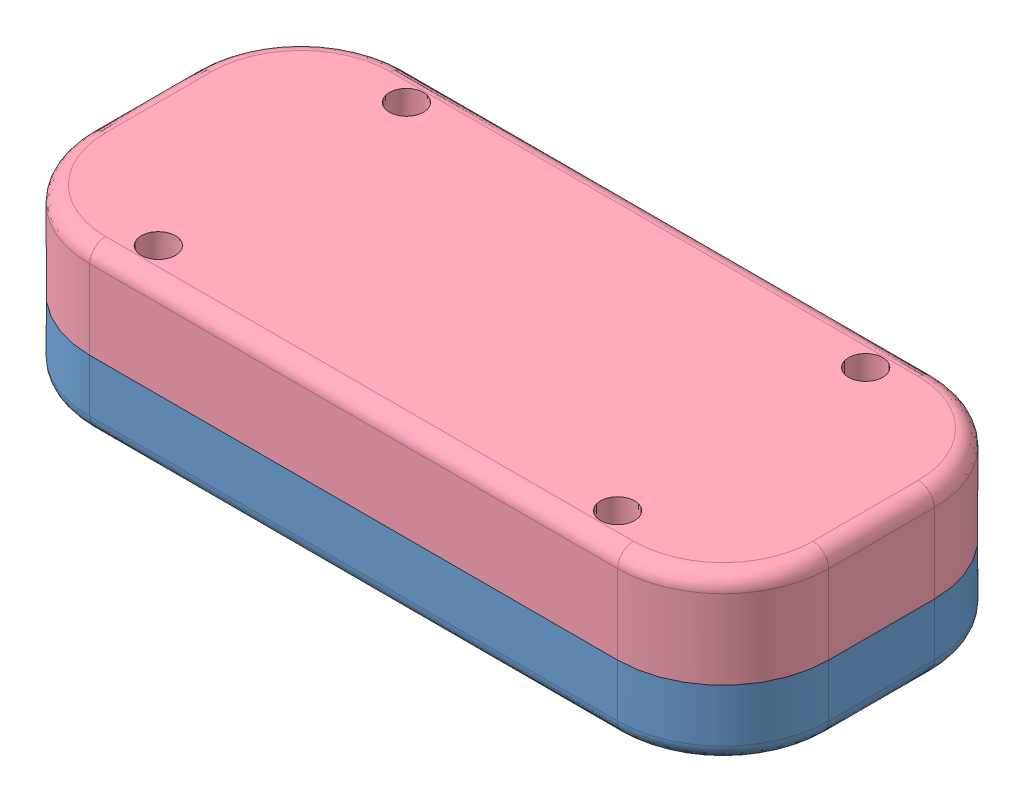
SolidWorks assembly TES, configuration Default. Lengths in mm.
Overall size (140 31 62.5).
89 component instances, 21 part files, 17 mates.
Components (placement in the parent):
- TES-top-1: TES-top [Default] at (48.5588 53.8768 118.0307) size (140 13 60)
- SPI-TFT-320X240-1: SPI-TFT-320X240 [Default] at (50.0588 62.3768 118.0307) x (1 0 0) z (0 0 -1) size (77 14 43)
- D-Pad-1: D-Pad [Default] at (-3.5412 66.8768 117.9307) x (1 0 0) z (0 -1 0) size (25 40 7)
- D-Pad-2: D-Pad [Default] at (99.6588 66.8768 117.9307) x (1 0 0) z (0 -1 0) size (25 40 7)
- TES-bottom-1: TES-bottom [Default] at (48.5588 84.8768 118.0307) x (1 0 0) z (0 0 -1) size (140 18 60)
- RapberryPiZero-1: RapberryPiZero [Default] at (-2.6976 88.9734 113.4764) x (-1 0 0) z (0 0 1) size (65 4.45 30.6)
  - Raspberry_pizero_PCB-1: Raspberry_pizero_PCB [Default] at (-51.2564 20.0966 13.0542) size (65 1 30)
  - Micro USB_input_female (short)-SMT-1: Micro USB_input_female (short)-SMT [Default] at (-42.3564 22.3216 25.8042) size (7.98 2.94 5.43)
  - Micro USB_input_female (short)-SMT-2: Micro USB_input_female (short)-SMT [Default] at (-29.7564 22.3216 25.8042) size (7.98 2.94 5.43)
  - 0204 - Capacitor-1: 0204 - Capacitor [Default] at (-62.4121 21.3466 11.2398) size (1 0.5 0.6)
  - 0204 - Capacitor-2: 0204 - Capacitor [Default] at (-62.4121 21.3466 12.2528) size (1 0.5 0.6)
  - 0204 - Capacitor-3: 0204 - Capacitor [Default] at (-61.8122 21.3466 13.3136) size (1 0.5 0.6)
  - 0204 - Capacitor-4: 0204 - Capacitor [Default] at (-61.8122 21.3466 14.2646) size (1 0.5 0.6)
  - 0204 - Capacitor-5: 0204 - Capacitor [Default] at (-61.8122 21.3466 15.241) size (1 0.5 0.6)
  - 0204 - Capacitor-6: 0204 - Capacitor [Default] at (-61.8122 21.3466 16.2144) size (1 0.5 0.6)
  - 0204 - Capacitor-7: 0204 - Capacitor [Default] at (-61.8122 21.3466 17.2416) size (1 0.5 0.6)
  - 0204 - Capacitor-8: 0204 - Capacitor [Default] at (-62.5919 21.3466 20.9695) size (1 0.5 0.6)
  - 0204 - Capacitor-9: 0204 - Capacitor [Default] at (-62.5919 21.3466 21.919) size (1 0.5 0.6)
  - 0204 - Capacitor-10: 0204 - Capacitor [Default] at (-60.4584 21.3466 22.3712) x (0 0 1) z (-1 0 0) size (1 0.5 0.6)
  - 0204 - Capacitor-11: 0204 - Capacitor [Default] at (-60.0807 21.3466 22.3712) x (0 0 -1) z (1 0 0) size (1 0.5 0.6)
  - 0204 - Capacitor-12: 0204 - Capacitor [Default] at (-59.0466 21.3466 22.3712) x (0 0 -1) z (1 0 0) size (1 0.5 0.6)
  - 0204 - Capacitor-13: 0204 - Capacitor [Default] at (-52.6496 21.3466 22.316) x (0 0 1) z (-1 0 0) size (1 0.5 0.6)
  - 0204 - Capacitor-14: 0204 - Capacitor [Default] at (-52.25 21.3466 22.316) x (0 0 -1) z (1 0 0) size (1 0.5 0.6)
  - 0204 - Capacitor-15: 0204 - Capacitor [Default] at (-51.2398 21.3466 22.316) x (0 0 -1) z (1 0 0) size (1 0.5 0.6)
  - 0204 - Capacitor-16: 0204 - Capacitor [Default] at (-49.1841 21.3466 22.316) x (0 0 -1) z (1 0 0) size (1 0.5 0.6)
  - 0204 - Capacitor-17: 0204 - Capacitor [Default] at (-48.1448 21.3466 22.316) x (0 0 -1) z (1 0 0) size (1 0.5 0.6)
  - 0204 - Capacitor-18: 0204 - Capacitor [Default] at (-46.475 21.3466 21.113) size (1 0.5 0.6)
  - 0204 - Capacitor-19: 0204 - Capacitor [Default] at (-45.7322 21.3466 20.0663) size (1 0.5 0.6)
  - 0204 - Capacitor-20: 0204 - Capacitor [Default] at (-45.7322 21.3466 19.0675) size (1 0.5 0.6)
  - 0204 - Capacitor-21: 0204 - Capacitor [Default] at (-45.7322 21.3466 18.1249) size (1 0.5 0.6)
  - 0204 - Capacitor-22: 0204 - Capacitor [Default] at (-45.7322 21.3466 17.1095) size (1 0.5 0.6)
  - 0204 - Capacitor-23: 0204 - Capacitor [Default] at (-46.3457 21.3466 16.1412) size (1 0.5 0.6)
  - 0204 - Capacitor-24: 0204 - Capacitor [Default] at (-46.3457 21.3466 15.1229) size (1 0.5 0.6)
  - 0204 - Capacitor-25: 0204 - Capacitor [Default] at (-46.3457 21.3466 14.0197) size (1 0.5 0.6)
  - 0204 - Capacitor-26: 0204 - Capacitor [Default] at (-46.3457 21.3466 12.9589) size (1 0.5 0.6)
  - 0204 - Capacitor-27: 0204 - Capacitor [Default] at (-43.6156 21.3466 13.1418) size (1 0.5 0.6)
  - 0204 - Capacitor-28: 0204 - Capacitor [Default] at (-43.6156 21.3466 10.1424) size (1 0.5 0.6)
  - 0204 - Capacitor-29: 0204 - Capacitor [Default] at (-48.9117 21.3466 7.6917) size (1 0.5 0.6)
  - 0204 - Capacitor-30: 0204 - Capacitor [Default] at (-55.4926 21.3466 7.2526) x (0 0 -1) z (1 0 0) size (1 0.5 0.6)
  - 0204 - Capacitor-31: 0204 - Capacitor [Default] at (-53.7932 21.3466 7.2526) x (0 0 1) z (-1 0 0) size (1 0.5 0.6)
  - 0204 - Capacitor-32: 0204 - Capacitor [Default] at (-59.8477 21.3466 7.2526) x (0 0 1) z (-1 0 0) size (1 0.5 0.6)
  - 0204- Resistor-15: 0204- Resistor [Default] at (-43.6109 21.4522 15.4193) x (-1 0 0) z (0 -1 0) size (0.99 0.51 0.36)
  - 0204- Resistor-14: 0204- Resistor [Default] at (-43.6109 21.4522 14.4127) x (-1 0 0) z (0 -1 0) size (0.99 0.51 0.36)
  - 0204- Resistor-13: 0204- Resistor [Default] at (-43.6109 21.4522 12.4047) x (-1 0 0) z (0 -1 0) size (0.99 0.51 0.36)
  - 0204- Resistor-4: 0204- Resistor [Default] at (-42.6936 21.4522 18.4076) x (-1 0 0) z (0 -1 0) size (0.99 0.51 0.36)
  - 0204- Resistor-5: 0204- Resistor [Default] at (-39.831 21.4522 18.1462) x (0 0 1) z (0 -1 0) size (0.99 0.51 0.36)
  - 0204- Resistor-7: 0204- Resistor [Default] at (-61.8169 21.4522 19.8533) x (-1 0 0) z (0 -1 0) size (0.99 0.51 0.36)
  - 0204- Resistor-8: 0204- Resistor [Default] at (-61.8169 21.4522 18.5178) x (-1 0 0) z (0 -1 0) size (0.99 0.51 0.36)
  - 0204- Resistor-9: 0204- Resistor [Default] at (-79.148 21.4522 17.7279) x (-1 0 0) z (0 -1 0) size (0.99 0.51 0.36)
  - 0204- Resistor-10: 0204- Resistor [Default] at (-56.0985 21.4522 7.2479) x (0 0 -1) z (0 -1 0) size (0.99 0.51 0.36)
  - 0204- Resistor-11: 0204- Resistor [Default] at (-28.0827 21.4522 9.5819) x (-1 0 0) z (0 -1 0) size (0.99 0.51 0.36)
  - 0204- Resistor-12: 0204- Resistor [Default] at (-21.8613 21.4522 20.9026) x (-1 0 0) z (0 -1 0) size (0.99 0.51 0.36)
  - CAP-0306-1: CAP-0306 [Default] at (-45.8903 21.4966 8.7634) size (1.6 0.8 0.9)
  - CAP-0306-2: CAP-0306 [Default] at (-82.0031 21.4966 19.0464) x (0 0 1) z (-1 0 0) size (1.6 0.8 0.9)
  - Raspberry_pizero_BCM2835 with VC4-2: Raspberry_pizero_BCM2835 with VC4 [Default] at (-54.1608 21.5466 15.1238) x (1 0 0) z (0 0 -1) size (12 0.65 12)
  - Crystal 3.4x2.4mm-1: Crystal 3.4x2.4mm [Default] at (-65.3089 21.0966 19.2633) size (3.2 1 2.4)
  - 0204- Resistor-16: 0204- Resistor [Default] at (-68.4329 21.4522 5.4384) x (0 0 1) z (0 -1 0) size (0.99 0.51 0.36)
  - 0204- Resistor-17: 0204- Resistor [Default] at (-69.7255 21.4522 5.4384) x (0 0 1) z (0 -1 0) size (0.99 0.51 0.36)
  - 0204- Resistor-18: 0204- Resistor [Default] at (-65.0626 21.4522 16.5355) x (1 0 0) z (0 -1 0) size (0.99 0.51 0.36)
  - 32,768 Khz Crystal-1: 32,768 Khz Crystal [Default] at (-60.5154 21.1428 26.5473) x (0.999848 -0.017452 0) z (0 0 1) size (3.4 1.03 1.5)
  - 0805- Capacitor-1: 0805- Capacitor [Default] at (-51.9496 21.9966 5.2384) x (1 0 0) z (0 -1 0) size (2 1.25 0.9)
  - 0805- Capacitor-2: 0805- Capacitor [Default] at (-51.9496 21.9966 7.3589) x (1 0 0) z (0 -1 0) size (2 1.25 0.9)
  - 0805- Capacitor-3: 0805- Capacitor [Default] at (-37.009 21.9966 22.5384) x (0 0 -1) z (0 -1 0) size (2 1.25 0.9)
  - 0805- Capacitor-4: 0805- Capacitor [Default] at (-29.8247 21.9966 13.3538) x (0 0 1) z (0 -1 0) size (2 1.25 0.9)
  - 0805- Capacitor-5: 0805- Capacitor [Default] at (-27.9052 21.9966 13.3538) x (0 0 -1) z (0 -1 0) size (2 1.25 0.9)
  - 0805- Capacitor-6: 0805- Capacitor [Default] at (-22.8003 21.9966 13.3538) x (0 0 -1) z (0 -1 0) size (2 1.25 0.9)
  - 0805- Capacitor-7: 0805- Capacitor [Default] at (-20.9924 21.9966 13.3538) x (0 0 -1) z (0 -1 0) size (2 1.25 0.9)
  - 0204- Resistor-19: 0204- Resistor [Default] at (-48.8769 21.4522 23.8207) x (1 0 0) z (0 -1 0) size (0.99 0.51 0.36)
  - 0204- Resistor-20: 0204- Resistor [Default] at (-52.4165 21.4522 24.0419) x (1 0 0) z (0 -1 0) size (0.99 0.51 0.36)
  - 0204 - Capacitor-33: 0204 - Capacitor [Default] at (-47.1199 21.3466 23.926) x (0 0 1) z (-1 0 0) size (1 0.5 0.6)
  - 0204 - Capacitor Brown-34: 0204 - Capacitor Brown [Default] at (-57.5817 21.3466 26.803) size (1 0.5 0.6)
  - 0204 - Capacitor Brown-35: 0204 - Capacitor Brown [Default] at (-64.0312 21.3466 26.8794) size (1 0.5 0.6)
  - 0204 - Capacitor Brown-36: 0204 - Capacitor Brown [Default] at (-46.3457 21.3466 12.214) size (1 0.5 0.6)
  - 0204 - Capacitor Brown-37: 0204 - Capacitor Brown [Default] at (-46.3457 21.3466 11.0963) size (1 0.5 0.6)
  - 0204 - Capacitor Brown-38: 0204 - Capacitor Brown [Default] at (-46.3457 21.3466 10.1566) size (1 0.5 0.6)
  - 0204 - Capacitor Brown-39: 0204 - Capacitor Brown [Default] at (-43.6156 21.3466 11.1151) size (1 0.5 0.6)
  - 0204 - Capacitor Brown-40: 0204 - Capacitor Brown [Default] at (-28.0874 21.3466 10.3236) size (1 0.5 0.6)
  - 0204 - Capacitor Brown-41: 0204 - Capacitor Brown [Default] at (-80.6197 21.3466 20.6997) size (1 0.5 0.6)
  - 0204- Resistor-21: 0204- Resistor [Default] at (-78.9105 21.4522 21.1554) x (1 0 0) z (0 -1 0) size (0.99 0.51 0.36)
  - 6-Pin SOT-1: 6-Pin SOT [Default] at (-79.714 21.0966 19.2138) x (0 0 1) z (0 1 0) size (1.5 1.84 0.95)
  - micro sd molex-1: micro sd molex [Default] at (-74.7768 21.6766 -33.0961) x (0 0 1) z (0 1 0) size (11.95 11.4 1.45)
  - hdmi type C-1: hdmi type C [Default] at (-71.3564 22.9466 28.6542) size (12.9 4.05 7.7)
  - Voltage Regulator 3x3mm 12-Pin-1: Voltage Regulator 3x3mm 12-Pin [Default] at (-23.6842 21.0966 12.6105) x (1 0 0) z (0 1 0) size (3 4.1 1.2)
  - 1210 inductor-1: 1210 inductor [Default] at (-46.4963 21.0916 6.3909) x (0 0 1) z (0 1 0) size (3.26 2.86 0.75)
  - 1210 inductor-2: 1210 inductor [Default] at (-22.7405 21.0916 9.2394) x (1 0 0) z (0 1 0) size (3.26 2.86 0.75)
  - 1210 inductor-3: 1210 inductor [Default] at (-28.2854 21.0916 17.6682) x (1 0 0) z (0 1 0) size (3.26 2.86 0.75)
  - 0204 - Capacitor-34: 0204 - Capacitor [Default] at (-48.9117 21.3466 6.5273) size (1 0.5 0.6)
- micro-usb-breakout-1: micro-usb-breakout [Default] at (70.0588 79.8768 98.0307) x (-1 0 0) z (0 0 1) size (21 5 12.5)
- power-1: power [Default] at (31.5588 75.8768 95.5307) x (-1 0 0) z (0 -1 0) size (43 10 10.1)
Mates (geometry in assembly coordinates):
- Coincident2: coincident anti-aligned: plane of TES-top-1 through (14.8088 60.3768 99.7807) normal (0 1 0); plane of SPI-TFT-320X240-1 through (50.0588 60.3768 118.0307) normal (0 -1 0)
- Concentric1: concentric anti-aligned: circle of TES-top-1; circle of SPI-TFT-320X240-1
- Concentric2: concentric anti-aligned: circle of TES-top-1; circle of SPI-TFT-320X240-1
- Coincident3: coincident anti-aligned: plane of TES-top-1 through (-3.5412 64.8768 101.7307) normal (0 1 0); plane of D-Pad-1 through (-3.5412 64.8768 117.9307) normal (0 -1 0)
- Concentric3: concentric anti-aligned: circle of TES-top-1; circle of D-Pad-1
- Coincident4: coincident anti-aligned: plane of TES-top-1 through (99.6588 64.8768 134.1307) normal (0 1 0); plane of D-Pad-2 through (99.6588 64.8768 117.9307) normal (0 -1 0)
- Concentric4: concentric anti-aligned: circle of TES-top-1; circle of D-Pad-2
- Coincident5: coincident anti-aligned: plane of TES-bottom-1 through (77.5588 68.8768 138.0307) normal (0 -1 0); plane of RapberryPiZero-1/Raspberry_pizero_PCB-1 through (78.0588 68.8768 114.5307) normal (0 1 0)
- Concentric5: concentric anti-aligned: circle of TES-bottom-1; circle of RapberryPiZero-1/Raspberry_pizero_PCB-1
- Concentric6: concentric aligned: circle of TES-bottom-1; circle of RapberryPiZero-1/Raspberry_pizero_PCB-1
- Coincident6: coincident anti-aligned: plane of TES-bottom-1 through (62.5588 79.8768 95.0307) normal (0 -1 0); plane of micro-usb-breakout-1 through (70.0588 79.8768 98.0307) normal (0 1 0)
- Concentric9: concentric aligned: circle of TES-bottom-1; circle of micro-usb-breakout-1
- Concentric11: concentric aligned: circle of TES-bottom-1; circle of micro-usb-breakout-1
- Coincident7: coincident anti-aligned: line of TES-top-1 through (98.5588 66.8768 88.0307) axis (-1 0 0); line of TES-bottom-1 through (-1.4412 66.8768 88.0307) axis (1 0 0)
- Coincident8: coincident anti-aligned: line of TES-top-1 through (-21.4412 66.8768 108.0307) axis (0 0 1); line of TES-bottom-1 through (-21.4412 66.8768 128.0307) axis (0 0 -1)
- Coincident13: coincident anti-aligned: circle of TES-bottom-1; circle of power-1
- Coincident14: coincident anti-aligned: circle of TES-bottom-1; circle of power-1
